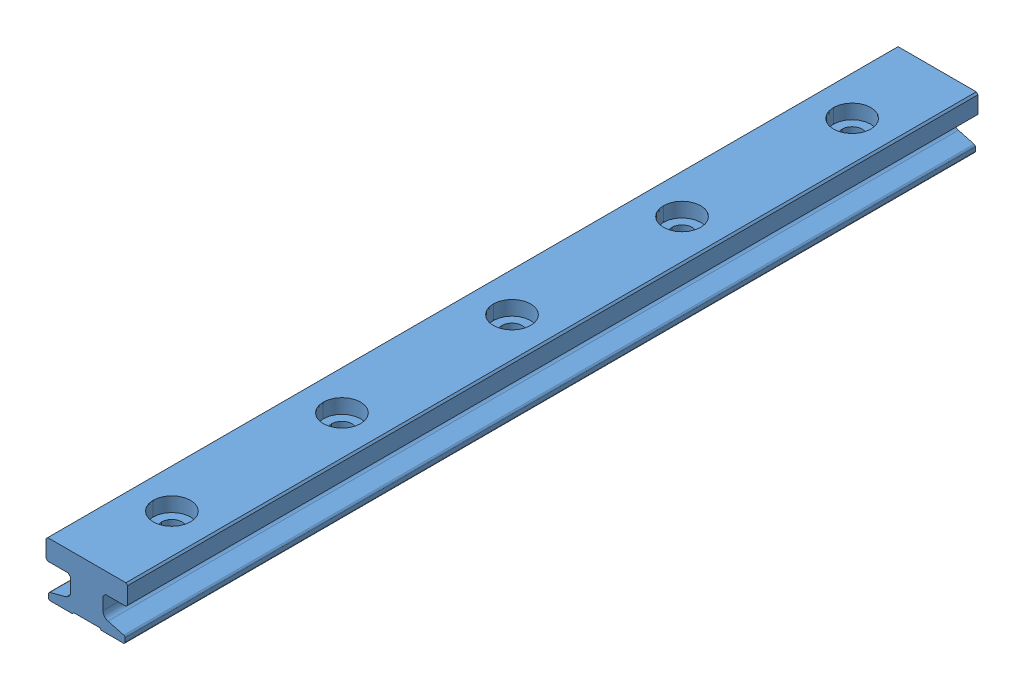
SolidWorks assembly needle_driveactive_base, configuration Default. Lengths in mm.
Overall size (9.6 6.3 100).
3 component instances, 3 part files, 15 mates.
Components (placement in the parent):
- rail_TS_04_09_50_1.SLDPTactive-1: rail_TS_04_09_50_1.SLDPTactive [Default] at (114.2812 79.3988 -72.1414) x (1 0 0) z (0 1 0) size (9.6 100 6.3)
- end_stopactive-1: end_stopactive [Default] at (114.2852 82.675 -157.1414) x (-1 0 0) z (0 -1 0) size (15.1 25.11 12.45) (hidden)
- cable_clampactive-1: cable_clampactive [Default] at (109.0312 68.5988 -107.174) x (0 0 -1) z (1 0 0) size (22.06 11.5 6.5) (hidden)
Mates (geometry in assembly coordinates):
- Coincident15: coincident: plane of ? through (118.0312 85.6988 -103.974) normal (0 -1 0); plane of rail_TS_04_09_50_1.SLDPTactive-1 through (111.9812 85.6988 -47.1414) normal (0 1 0)
- Coincident16: coincident: plane of ? through (119.0812 84.4988 -103.974) normal (-1 0 0); plane of rail_TS_04_09_50_1.SLDPTactive-1 through (119.0812 84.4988 -47.1414) normal (1 0 0)
- Coincident28: coincident: plane of rail_TS_04_09_50_1.SLDPTactive-1 through (111.2812 79.3988 -47.1414) normal (0 -1 0); plane of end_stopactive-1 through (118.5773 79.3988 -162.1414) normal (0 1 0)
- Concentric15: concentric: cylinder of rail_TS_04_09_50_1.SLDPTactive-1 through (114.2812 81.7888 -152.1414) axis (0 1 0) radius 1.2; cylinder of end_stopactive-1 through (114.2812 79.3988 -152.1414) axis (0 1 0) radius 1.3526
- Coincident30: coincident: plane of ? through (107.0312 89.3988 -109.174) normal (0 1 0); plane of ? through (105.7812 89.3988 -132.674) normal (0 -1 0)
- Concentric19: concentric: cylinder of ? through (121.7812 85.7988 -124.674) axis (0 1 0) radius 0.7835; cylinder of ? through (121.7812 92.3988 -124.674) axis (0 1 0) radius 1.2
- Concentric20: concentric: cylinder of ? through (106.7812 85.7988 -111.674) axis (0 1 0) radius 0.7835; cylinder of ? through (106.7812 92.3988 -111.674) axis (0 1 0) radius 1.2
- Concentric21: concentric: cylinder of ? through (114.2812 102.0238 -91.674) axis (0 0 -1) radius 6.5; cylinder of ? through (114.2812 102.0238 -91.674) axis (0 0 -1) radius 5.625
- Coincident31: coincident: plane of ? through (114.2812 102.0238 -91.674) normal (0 0 1); plane of ? through (114.2812 102.0238 -91.674) normal (0 0 -1)
- Coincident32: coincident: plane of ? through (108.0686 81.0988 -109.174) normal (0 -1 0); plane of cable_clampactive-1 through (109.0312 81.0988 -107.174) normal (0 1 0)
- Concentric22: concentric: cylinder of ? through (106.7812 85.7988 -111.674) axis (0 1 0) radius 0.7835; cylinder of cable_clampactive-1 through (106.7812 81.0988 -111.674) axis (0 1 0) radius 1.1
- Concentric23: concentric: cylinder of ? through (106.7812 85.7988 -124.674) axis (0 1 0) radius 0.7835; cylinder of cable_clampactive-1 through (106.7812 81.0988 -124.674) axis (0 1 0) radius 1.1
- Concentric24: concentric: cylinder of ? through (17.6019 29.9653 -33.2982) axis (0 1 0) radius 0.7835; circle of ?
- Concentric25: concentric: cylinder of ? through (17.6019 29.9653 -46.2982) axis (0 1 0) radius 0.7835; cylinder of ? through (17.6019 25.2653 -46.2982) axis (0 1 0) radius 1.1
- Coincident33: coincident: plane of ? through (16.3146 25.2653 -30.7982) normal (0 -1 0); plane of ? through (15.3519 25.2653 -50.7982) normal (0 1 0)
